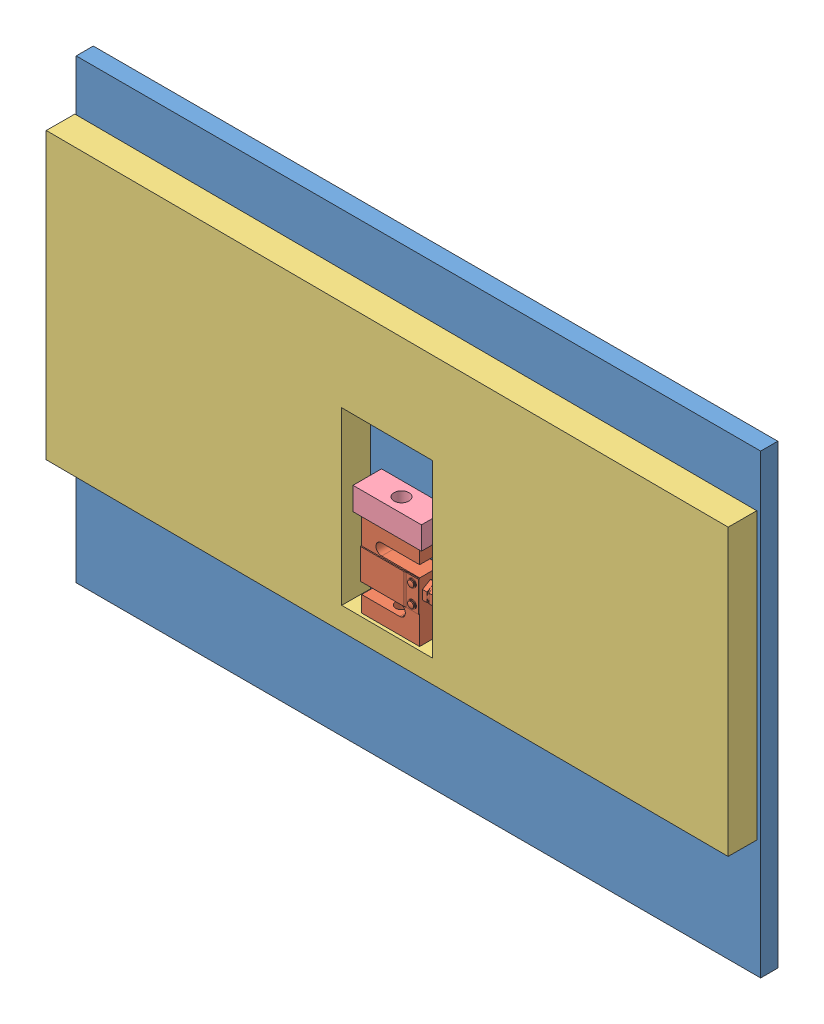
SolidWorks assembly Ensamblaje_WallBench_V2, configuration Predeterminado. Lengths in mm.
Overall size (1620.03 710.14 44.38).
4 component instances, 4 part files, 9 mates.
Components (placement in the parent):
- Wall-1: Wall [Predeterminado] at (-300 -200 -15) x (-1 0 0) z (0 0 1) size (600 400 15)
- S-beam_load_cell_FS6B-2: S-beam_load_cell_FS6B [默认] at (-299.0844 -234.5101 15.75) size (1344.52 582.75 25)
- Bottom_support-1: Bottom_support [Predeterminado] at (-299.0373 -167.6101 3.2501) x (0.999993 0 0.003766) z (-0.003766 0 0.999993) size (600 250 25)
- Top_support-1: Top_support [Predeterminado] at (-299.0844 -186.4101 3.25) size (60 20 25)
Mates (geometry in assembly coordinates):
- Coincidente3: coincident: point of Wall-1; point of assembly
- Paralelo3: parallel anti-aligned: plane of Wall-1 through (-300 -200 -15) normal (0 0 -1); plane of assembly through (0 0 0) normal (0 0 1)
- Paralelo4: parallel anti-aligned: plane of Wall-1 through (0 -400 0) normal (0 -1 0); plane of assembly through (0 0 0) normal (0 1 0)
- Distancia1: distance = 5 mm anti-aligned: plane of S-beam_load_cell_FS6B-2 through (-286.6377 -221.2601 5) normal (0 0 -1); plane of Wall-1 through (-300 -200 0) normal (0 0 1)
- Concéntrica1: concentric aligned: cylinder of S-beam_load_cell_FS6B-2 through (-299.0844 -272.6101 15.75) axis (0 -1 0) radius 5.1; cylinder of Bottom_support-1 through (-299.0844 -42.6091 15.75) axis (0 -1 0) radius 6.5
- Coincidente4: coincident anti-aligned: plane of S-beam_load_cell_FS6B-2 through (-273.6844 -272.6101 25.25) normal (0 -1 0); plane of Bottom_support-1 through (-339.1312 -272.6101 28.0993) normal (0 1 0)
- Concéntrica2: concentric aligned: cylinder of S-beam_load_cell_FS6B-2 through (-299.0844 -196.4101 15.75) axis (0 1 0) radius 5.1; circle of Top_support-1
- Coincidente5: coincident anti-aligned: plane of S-beam_load_cell_FS6B-2 through (-273.6844 -196.4101 25.25) normal (0 1 0); plane of Top_support-1 through (-329.0844 -196.4101 28.25) normal (0 -1 0)
- Paralelo5: parallel anti-aligned: plane of Wall-1 through (-300 -200 0) normal (0 0 1); plane of Top_support-1 through (-299.0844 -186.4101 3.25) normal (0 0 -1)
